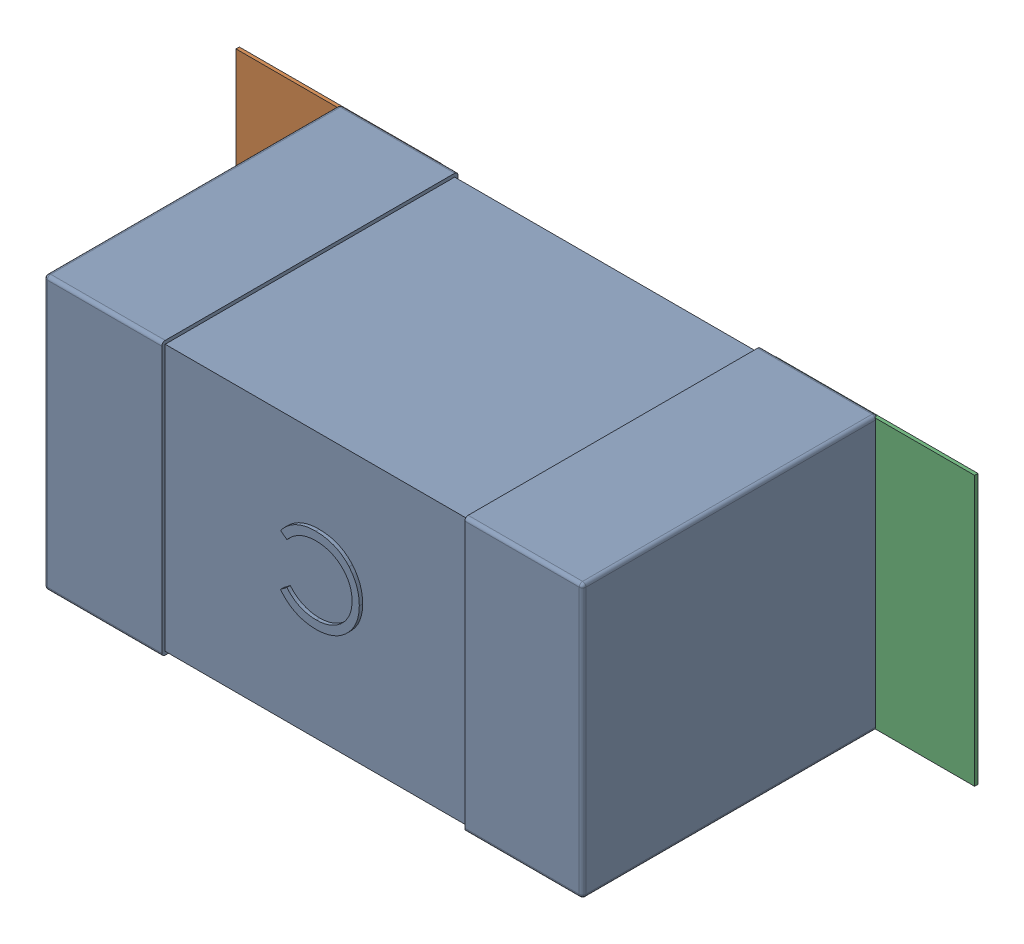
SolidWorks assembly C40, configuration Défaut. Lengths in mm.
Overall size (2.19 0.81 0.88).
5 component instances, 2 part files, 0 mates.
Components (placement in the parent):
- 0603_C-1: 0603_C [Défaut] at (6.2513 -9.0228 0) x (-1 0 0) z (0 0 1) size (1.6 0.81 0.88)
- 6634915696-1: 6634915696 [Défaut] at (5.0013 -9.0228 0) size (0.6 0.8 0.01)
  - Extruded_497-1: Extruded_497 [Défaut] at origin size (0.6 0.8 0.01)
- 6634915696-2: 6634915696 [Défaut] at (6.5962 -9.0228 0) size (0.6 0.8 0.01)
  - Extruded_497-1: Extruded_497 [Défaut] at origin size (0.6 0.8 0.01)
